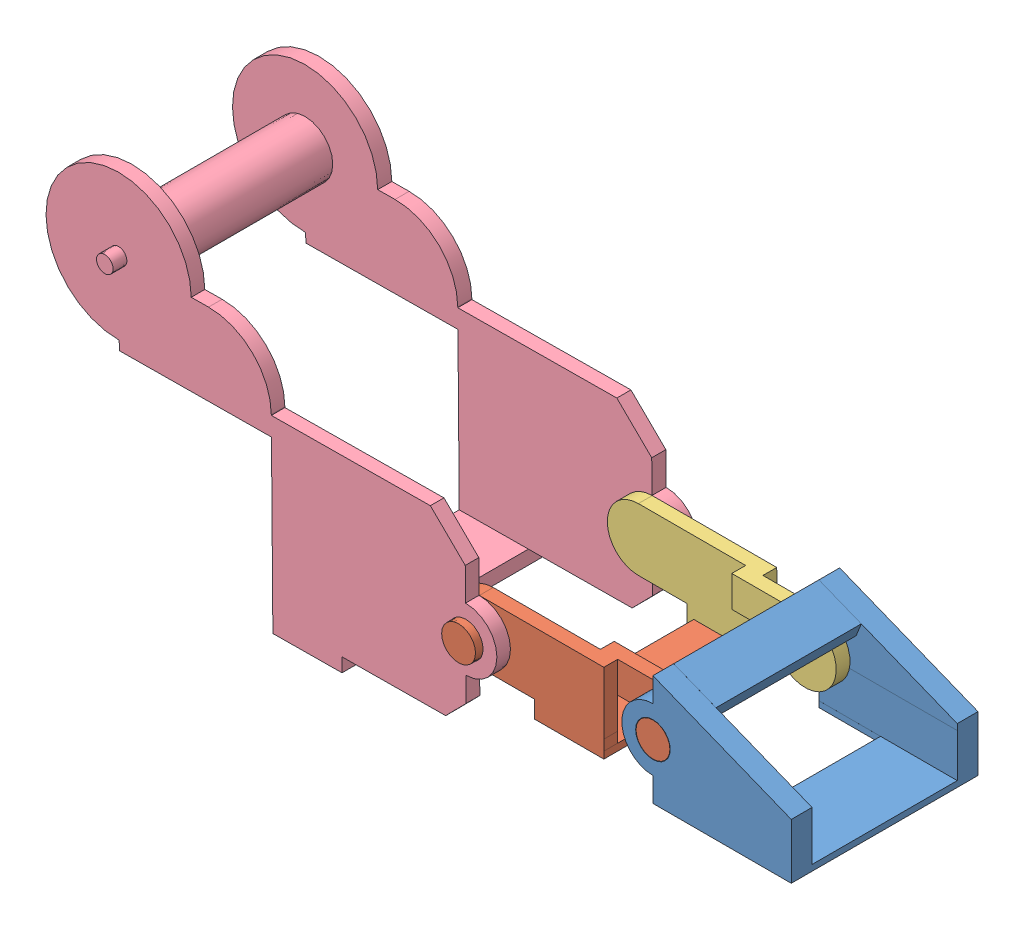
SolidWorks assembly 组装, configuration 默认. Lengths in mm.
Overall size (106.88 47.35 33).
4 component instances, 4 part files, 7 mates.
Components (placement in the parent):
- 指头-1: 指头 [默认] at (4.853 -1.9363 13.5) size (25 16 27)
- 中指节右-1: 中指节右 [默认] at (48.3008 8.9981 37.4965) x (1 0.000245 0) z (0 0 1) size (35.1 11.5 28)
- 中指节左-1: 中指节左 [默认] at (48.3008 8.9981 16.4965) x (1 0.000245 0) z (0 0 1) size (35.1 12.6 7)
- 后指头左-1: 后指头左 [默认] at (-34.4835 -12.1672 12.4585) x (0.999965 0.008407 0) z (0 0 1) size (65 46.8 33)
Mates (geometry in assembly coordinates):
- 同心2: concentric aligned: cylinder of 指头-1 through (-4.058 1.1749 53.5) axis (0 0 -1) radius 2.5; cylinder of 中指节右-1 through (-4.058 1.1749 40.4965) axis (0 0 -1) radius 2.45
- 同心3: concentric anti-aligned: cylinder of 指头-1 through (-4.058 1.1749 53.5) axis (0 0 -1) radius 2.5; cylinder of 中指节左-1 through (-4.058 1.1749 13.4965) axis (0 0 1) radius 2.45
- 重合1: coincident anti-aligned: plane of 中指节右-1 through (48.3008 8.9981 14.4965) normal (0 0 -1); plane of 中指节左-1 through (48.3008 8.9981 14.4965) normal (0 0 1)
- 平行2: parallel: plane of 中指节右-1 through (-22.1541 -5.8295 39.4965) normal (0.000245 -1 0); line of 中指节左-1 through (-21.1541 -5.9293 14.4965) axis (1 0.000245 0)
- 重合7: coincident anti-aligned: plane of 指头-1 through (-24.058 -1.9363 37.4965) normal (0 0 -1); plane of 中指节右-1 through (48.3008 8.9981 37.4965) normal (0 0 1)
- 同心4: concentric anti-aligned: cylinder of 中指节左-1 through (-30.158 1.1685 11.4965) axis (0 0 1) radius 2.45; cylinder of 后指头左-1 through (-30.158 1.1685 41.4585) axis (0 0 -1) radius 2.5002
- 重合8: coincident anti-aligned: plane of 中指节左-1 through (48.3008 8.9981 14.4965) normal (0 0 -1); plane of 后指头左-1 through (-48.4852 40.0148 14.4965) normal (0 0 1)
